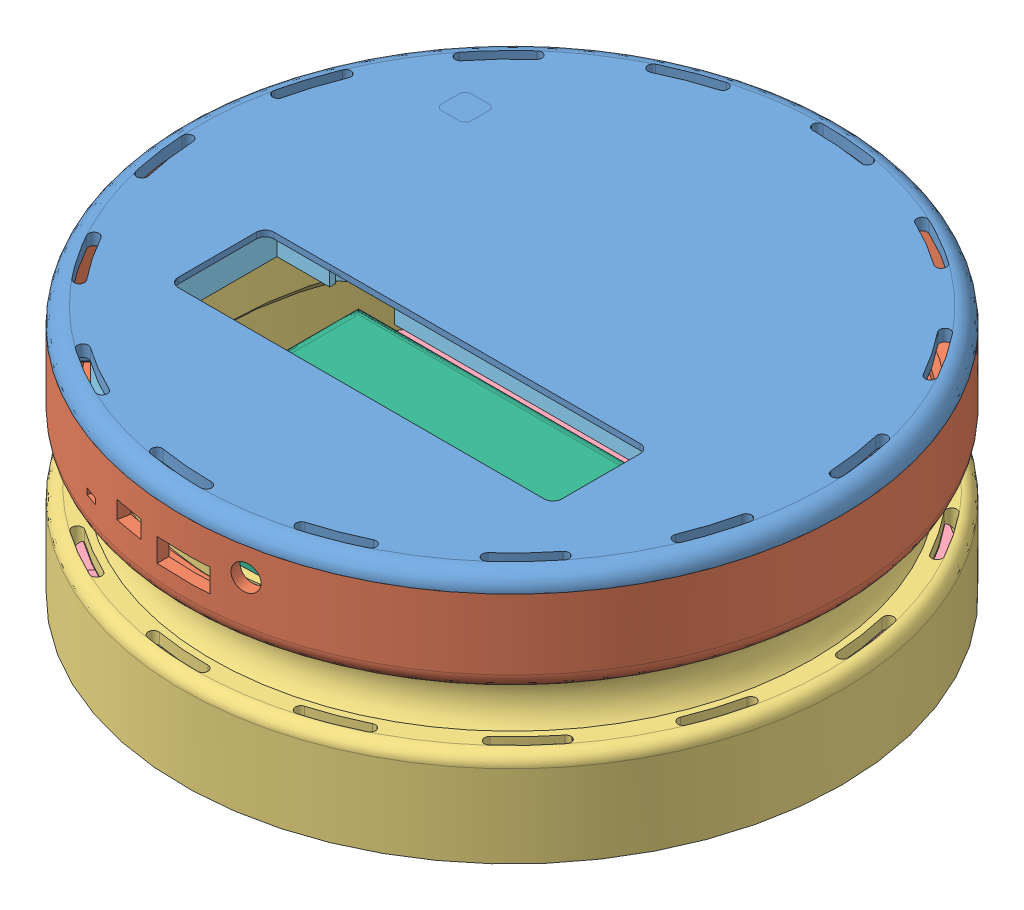
SolidWorks assembly Enclosure Assembly, configuration Default. Lengths in mm.
Overall size (112 42.5 112).
14 component instances, 13 part files, 9 mates.
Components (placement in the parent):
- Enclosure master-1: Enclosure master [Default] at origin size (56 42.5 0)
- Enclosure top plate-1: Enclosure top plate [Default] at origin size (112 5.3 112)
- Enclosure middle upper-1: Enclosure middle upper [Default] at origin size (112 15.5 112)
- Enclosure middle lower-1: Enclosure middle lower [Default] at origin size (112 29 112)
- Enclosure bottom plate-1: Enclosure bottom plate [Default] at origin size (112 5.3 112)
- Enclosure internal guides-1: Enclosure internal guides [Default] at origin size (94.61 9.2 97.14)
- Enclosure battery holder 18650x2-1: Enclosure battery holder 18650x2 [Default] at origin size (75.25 19.85 39.4)
- Enclosure battery holder LiPo flat 2500mAh-1: Enclosure battery holder LiPo flat 2500mAh [Default] at origin (hidden)
- Enclosure light sensor tube-1: Enclosure light sensor tube [Default] at origin size (9.4 9.1 9.01)
- Enclosure PCB clips-1: Enclosure PCB clips [Default] at origin size (11.79 16.37 11.68)
- Enclosure PCB clips-2: Enclosure PCB clips [Default] at (63.6008 0 -2.221) x (0.997564 0 -0.069756) z (0.069756 0 0.997564) size (11.79 16.37 11.68)
- Enclosure slide clip-1: Enclosure slide clip [Default] at (-48.2 -0.1 0) size (2.8 4.7 10.9)
- PCB 3D model-2: PCB 3D model [Default] at (78.08 29.4243 75.8377) x (-1 0 0) z (0 -1 0) size (90 100.86 19.54) (hidden)
- Enclosure PCB model-1: Enclosure PCB model [Default] at origin size (90 12.1 101.39) (hidden)
Mates (geometry in assembly coordinates):
- Concentric1: concentric aligned: circle of Enclosure top plate-1; circle of PCB 3D model-2
- Distance4: distance = 9.5 mm anti-aligned: plane of PCB 3D model-2 through (22.5 31 38.9647) normal (0 1 0); plane of Enclosure top plate-1 through (0 40.5 0) normal (0 -1 0)
- Parallel4: parallel anti-aligned: plane of Enclosure top plate-1 through (0 40.5 0) normal (0 -1 0); plane of PCB 3D model-2 through (22.5 31 38.9647) normal (0 1 0)
- Concentric2: concentric aligned: circle of Enclosure PCB clips-2; circle of Enclosure top plate-1
- Coincident1: coincident anti-aligned: plane of Enclosure top plate-1 through (0 40.5 0) normal (0 -1 0); circle of Enclosure PCB clips-2
- LimitAngle1: limit planar angle = 1.570796 rad aligned: line of Enclosure top plate-1 through (34.1546 37.2 -32.4147) axis (-0.731354 0 -0.681998); line of Enclosure PCB clips-2 through (26.9679 39.05 -32.1453) axis (0.681998 0 -0.731354)
- LimitDistance1: limit distance = 0 mm anti-aligned: plane of Enclosure bottom plate-1 through (-51 0 3.85) normal (1 0 0); plane of Enclosure slide clip-1 through (-51 -0.1 0) normal (-1 0 0)
- Coincident3: coincident anti-aligned: plane of Enclosure bottom plate-1 through (0 5.3 3.85) normal (0 1 0); plane of Enclosure slide clip-1 through (-51 5.3 0) normal (0 -1 0)
- Distance5: distance = 0.1 mm anti-aligned: plane of Enclosure slide clip-1 through (-51 -0.1 -3.95) normal (0 0 1); plane of Enclosure bottom plate-1 through (0 0 -3.85) normal (0 0 -1)
